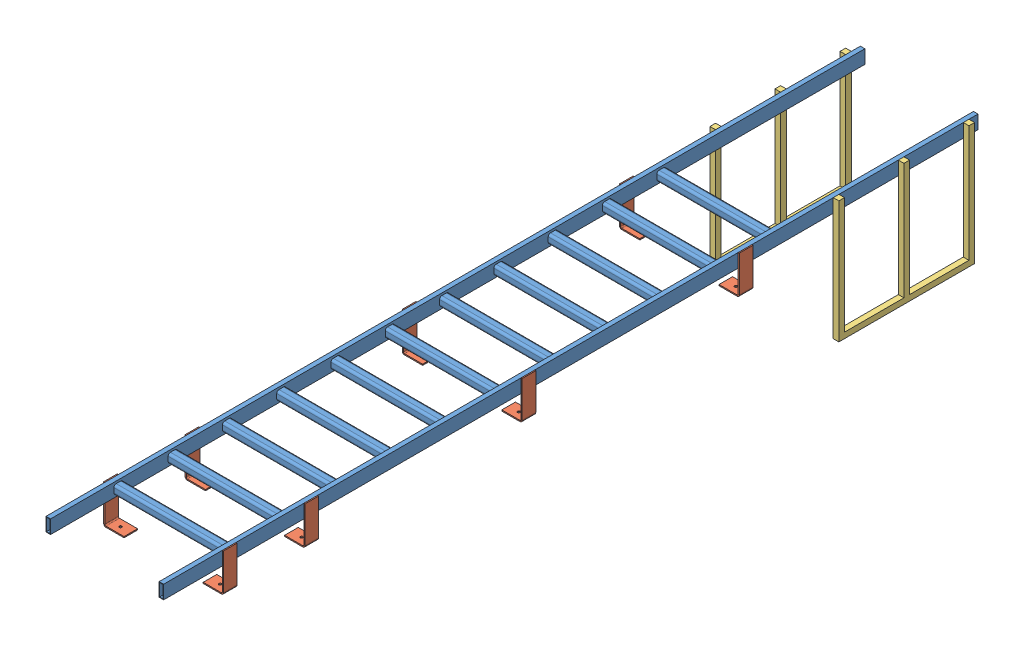
SolidWorks assembly Tubular Fixed Ladder, configuration Default. Lengths in mm.
Overall size (723.9 685.8 4572).
11 component instances, 3 part files, 7 mates.
Components (placement in the parent):
- Ladder-1: Ladder [Default<As Machined>] at (2669.0111 0 4319.9951) size (660.4 76.2 4572)
- Bracket-1: Bracket [Default<As Machined>] at (2338.8111 -69.85 5628.0951) x (0 1 0) z (1 0 0) size (215.9 76.2 114.3)
- Bracket-2: Bracket [Default<As Machined>] at (2338.8111 -69.85 6847.2951) x (0 1 0) z (1 0 0) size (215.9 76.2 114.3)
- Bracket-3: Bracket [Default<As Machined>] at (2338.8111 -69.85 8066.4951) x (0 1 0) z (1 0 0) size (215.9 76.2 114.3)
- Bracket-4: Bracket [Default<As Machined>] at (2999.2111 -69.85 5628.0951) x (0 1 0) z (-1 0 0) size (215.9 76.2 114.3)
- Bracket-5: Bracket [Default<As Machined>] at (2999.2111 -69.85 6847.2951) x (0 1 0) z (-1 0 0) size (215.9 76.2 114.3)
- Bracket-6: Bracket [Default<As Machined>] at (2999.2111 -69.85 8066.4951) x (0 1 0) z (-1 0 0) size (215.9 76.2 114.3)
- Bracket-7: Bracket [Default<As Machined>] at (2338.8111 -69.85 8523.6951) x (0 1 0) z (1 0 0) size (215.9 76.2 114.3)
- Bracket-8: Bracket [Default<As Machined>] at (2999.2111 -69.85 8523.6951) x (0 1 0) z (-1 0 0) size (215.9 76.2 114.3)
- Safety_tubes-1: Safety_tubes [Default<As Machined>] at (3015.0861 -631.825 4370.7951) size (31.75 685.8 762)
- Safety_tubes-4: Safety_tubes [Default<As Machined>] at (2322.9361 -631.825 5132.7951) x (-1 0 0) z (0 0 -1) size (31.75 685.8 762)
Mates (geometry in assembly coordinates):
- Coincident1: coincident anti-aligned: plane of Ladder-1 through (2338.8111 -38.1 8891.9951) normal (-1 0 0); plane of Bracket-1 through (2338.8111 -69.85 5628.0951) normal (1 0 0)
- Coincident2: coincident aligned: plane of Ladder-1 through (2364.2111 38.1 8891.9951) normal (0 1 0); plane of Bracket-1 through (2332.4611 38.1 5589.9951) normal (0 1 0)
- Distance1: distance = 1270 mm aligned: plane of Ladder-1 through (2669.0111 0 4319.9951) normal (0 0 -1); plane of Bracket-1 through (2332.4611 38.1 5589.9951) normal (0 0 -1)
- Coincident5: coincident aligned: plane of Ladder-1 through (2669.0111 0 4319.9951) normal (0 1 0)
- Coincident10: coincident aligned: plane of Ladder-1 through (2973.8111 38.1 8891.9951) normal (0 1 0); plane of Safety_tubes-1 through (3015.0861 38.1 3640.5451) normal (0 1 0)
- Distance4: distance = 304.8 mm anti-aligned: plane of Ladder-1 through (2973.8111 12.7 5437.5951) normal (0 0 -1); plane of Safety_tubes-1 through (3015.0861 -631.825 5132.7951) normal (0 0 1)
- Coincident13: coincident anti-aligned: plane of Ladder-1 through (2999.2111 -38.1 8891.9951) normal (1 0 0); plane of Safety_tubes-1 through (2999.2111 -647.7 5132.7951) normal (-1 0 0)
